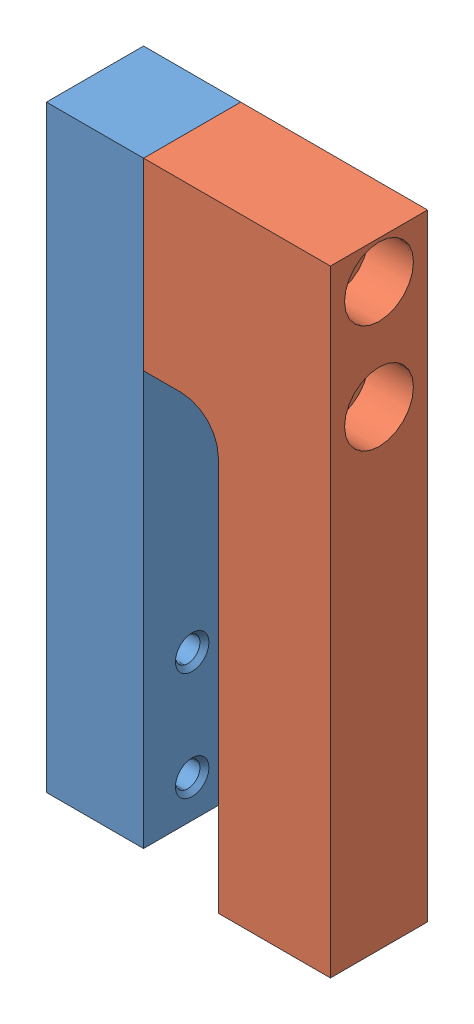
SolidWorks assembly vehicle_test_stand, configuration Default. Lengths in mm.
Overall size (38 82.5 20).
2 component instances, 2 part files, 4 mates.
Components (placement in the parent):
- loadcell-4: loadcell [Default] at (26.7779 68.3071 73.5181) x (0 -1 0) z (0 0 1) size (80 13 13)
- loadcell_mount_cal-1: loadcell_mount_cal [Default] at (39.7779 68.3071 73.5181) x (0 -1 0) z (1 0 0) size (82.5 13 25)
Mates (geometry in assembly coordinates):
- InPlace1: in place: plane of loadcell-4 through (39.7779 68.3071 73.5181) normal (1 0 0); plane of ? through (39.7779 0 0) normal (1 0 0); moOrthogonalPlaneRef_w of loadcell-4 through (39.7779 68.3071 73.5181) normal (1 0 0); plane of ? through (39.7779 0 0) normal (0 1 0); plane of loadcell-4 through (39.7779 68.3071 73.5181) normal (1 0 0); plane of ? through (39.7779 0 0) normal (0 0 -1); plane of loadcell-4 through (39.7779 68.3071 73.5181) normal (1 0 0); unknown of loadcell_mount_cal-1
- Coincident1: coincident aligned: plane of ?; plane of ?
- Coincident2: coincident aligned: moOrthogonalPlaneRef_w of loadcell-4 through (39.7779 68.3071 73.5181) normal (0 0 -1); plane of loadcell_mount-1 through (39.7779 68.3071 73.5181) normal (0 0 -1)
- Coincident3: coincident anti-aligned: moOrthogonalPlaneRef_w of loadcell-4 through (39.7779 68.3071 73.5181) normal (0 1 0); plane of loadcell_mount-1 through (39.7779 68.3071 73.5181) normal (0 -1 0)
